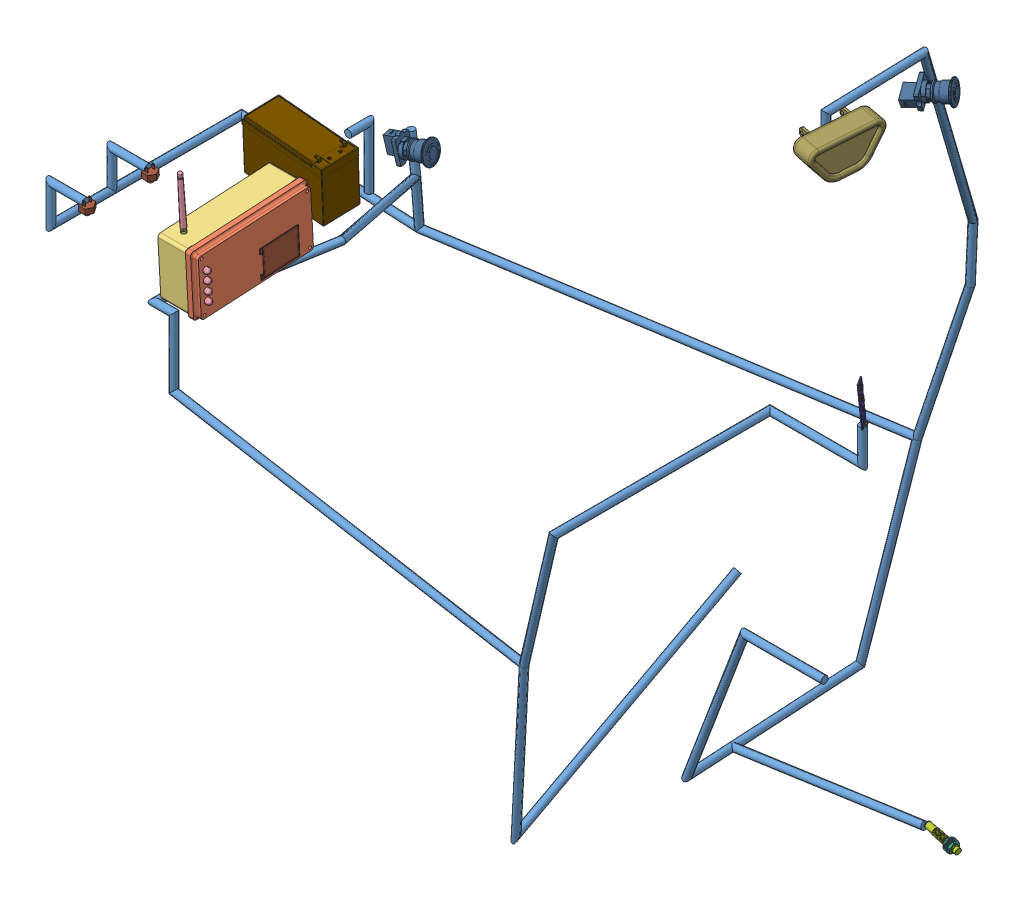
SolidWorks assembly Elétrica, configuration Valor predeterminado. Lengths in mm.
Overall size (1454.5 1161.28 753.93).
268 component instances, 110 part files, 2 mates.
Components (placement in the parent):
- Chicote elétrico-1: Chicote elétrico [Valor predeterminado<Como usinado>] at (-1115.3485 527.4134 1154.4841) size (1391.95 1161.28 753.93)
- Caixa_central-1: Caixa_central [Valor predeterminado] at (-1817.8838 498.4267 1275.2323) x (0 0.055168 -0.998477) z (1 0 0) size (209 203.94 79.26)
  - Caixa_frente-1: Caixa_frente [Valor predeterminado] at (-0.4442 -5.2196 199.5) size (209 109 19)
  - Caixa_traseira-1: Caixa_traseira [Valor predeterminado] at (-0.4442 -5.2196 199.5) size (204 104 52)
  - Placa_frontal_V1.0-1: Placa_frontal_V1.0 [Valor predeterminado] at (-98.9442 -54.7196 211.803) size (192 94 22.97)
    - Placa_frontal_V1.STEP-1: Placa_frontal_V1.STEP [Valor predeterminado] at origin size (192 94 22.97)
      - D1.STEP-1: D1.STEP [Valor predeterminado] at (11 74 0.803) x (-1 0 0) z (0 0 1) size (11 11 19.65)
        - Open CASCADE STEP translator 6.8 5.2.1.STEP-1: Open CASCADE STEP translator 6.8 5.2.1.STEP [Valor predeterminado] at origin size (11 11 19.65)
          - Body_1.STEP-1: Body_1.STEP [Valor predeterminado] at (1.25 0 -3.5) x (1 0 0) z (0 -1 0) size (11 19.65 11)
            - =_[0_1_1_3].STEP-1: =_[0_1_1_3].STEP [Valor predeterminado] at origin size (11 14 11)
            - =_[0_1_1_4].STEP-1: =_[0_1_1_4].STEP [Valor predeterminado] at origin size (0.5 5.65 0.5)
            - =_[0_1_1_5].STEP-1: =_[0_1_1_5].STEP [Valor predeterminado] at origin size (0.5 5.65 0.5)
            - =_[0_1_1_6].STEP-1: =_[0_1_1_6].STEP [Valor predeterminado] at origin size (0.6 0.65 0.5)
            - =_[0_1_1_7].STEP-1: =_[0_1_1_7].STEP [Valor predeterminado] at origin size (0.6 0.65 0.5)
      - D2.STEP-1: D2.STEP [Valor predeterminado] at (11 58 0.803) x (-1 0 0) z (0 0 1) size (11 11 19.65)
        - Open CASCADE STEP translator 6.8 5.3.1.STEP-1: Open CASCADE STEP translator 6.8 5.3.1.STEP [Valor predeterminado] at origin size (11 11 19.65)
          - Body_1.STEP-1: Body_1.STEP [Valor predeterminado] at (1.25 0 -3.5) x (1 0 0) z (0 -1 0) size (11 19.65 11)
            - =_[0_1_1_3].STEP-1: =_[0_1_1_3].STEP [Valor predeterminado] at origin size (11 14 11)
            - =_[0_1_1_4].STEP-1: =_[0_1_1_4].STEP [Valor predeterminado] at origin size (0.5 5.65 0.5)
            - =_[0_1_1_5].STEP-1: =_[0_1_1_5].STEP [Valor predeterminado] at origin size (0.5 5.65 0.5)
            - =_[0_1_1_6].STEP-1: =_[0_1_1_6].STEP [Valor predeterminado] at origin size (0.6 0.65 0.5)
            - =_[0_1_1_7].STEP-1: =_[0_1_1_7].STEP [Valor predeterminado] at origin size (0.6 0.65 0.5)
      - D3.STEP-1: D3.STEP [Valor predeterminado] at (11 41 0.803) x (-1 0 0) z (0 0 1) size (11 11 19.65)
        - Open CASCADE STEP translator 6.8 5.4.1.STEP-1: Open CASCADE STEP translator 6.8 5.4.1.STEP [Valor predeterminado] at origin size (11 11 19.65)
          - Body_1.STEP-1: Body_1.STEP [Valor predeterminado] at (1.25 0 -3.5) x (1 0 0) z (0 -1 0) size (11 19.65 11)
            - =_[0_1_1_3].STEP-1: =_[0_1_1_3].STEP [Valor predeterminado] at origin size (11 14 11)
            - =_[0_1_1_4].STEP-1: =_[0_1_1_4].STEP [Valor predeterminado] at origin size (0.5 5.65 0.5)
            - =_[0_1_1_5].STEP-1: =_[0_1_1_5].STEP [Valor predeterminado] at origin size (0.5 5.65 0.5)
            - =_[0_1_1_6].STEP-1: =_[0_1_1_6].STEP [Valor predeterminado] at origin size (0.6 0.65 0.5)
            - =_[0_1_1_7].STEP-1: =_[0_1_1_7].STEP [Valor predeterminado] at origin size (0.6 0.65 0.5)
      - D4.STEP-1: D4.STEP [Valor predeterminado] at (11 25 0.803) x (-1 0 0) z (0 0 1) size (11 11 19.65)
        - Open CASCADE STEP translator 6.8 5.5.1.STEP-1: Open CASCADE STEP translator 6.8 5.5.1.STEP [Valor predeterminado] at origin size (11 11 19.65)
          - Body_1.STEP-1: Body_1.STEP [Valor predeterminado] at (1.25 0 -3.5) x (1 0 0) z (0 -1 0) size (11 19.65 11)
            - =_[0_1_1_3].STEP-1: =_[0_1_1_3].STEP [Valor predeterminado] at origin size (11 14 11)
            - =_[0_1_1_4].STEP-1: =_[0_1_1_4].STEP [Valor predeterminado] at origin size (0.5 5.65 0.5)
            - =_[0_1_1_5].STEP-1: =_[0_1_1_5].STEP [Valor predeterminado] at origin size (0.5 5.65 0.5)
            - =_[0_1_1_6].STEP-1: =_[0_1_1_6].STEP [Valor predeterminado] at origin size (0.6 0.65 0.5)
            - =_[0_1_1_7].STEP-1: =_[0_1_1_7].STEP [Valor predeterminado] at origin size (0.6 0.65 0.5)
      - A1.STEP-1: A1.STEP [Valor predeterminado] at (96.2 24 0.803) size (85.9 50.19 11.99)
        - Open CASCADE STEP translator 6.8 5.6.1.STEP-1: Open CASCADE STEP translator 6.8 5.6.1.STEP [Valor predeterminado] at origin size (85.9 50.19 11.99)
          - Body_1-1.STEP-1: Body_1-1.STEP [Valor predeterminado] at (40.8 3.9 2.5) x (0 1 0) z (0 0 1) size (50.19 85.9 11.99)
            - 2.8in_TFT(Without_Glass)-_Tucked_Cable.STEP-1: 2.8in_TFT(Without_Glass)-_Tucked_Cable.STEP [Valor predeterminado] at (-0.0571 -2.2987 1.6256) x (-1 0 0) z (0 0 1) size (50.11 69.48 2.83)
              - SOLID.STEP-1: SOLID.STEP [Valor predeterminado] at origin size (0.29 0.77 0.02)
              - SOLID-0.STEP-1: SOLID-0.STEP [Valor predeterminado] at origin size (0.29 0.75 0.02)
              - SOLID-1.STEP-1: SOLID-1.STEP [Valor predeterminado] at origin size (50.11 69.48 2.72)
              - SOLID-2.STEP-1: SOLID-2.STEP [Valor predeterminado] at origin size (0.53 0.77 0.23)
            - 2.8_LCD_TFT_Module_-_Without_Glass.STEP-1: 2.8_LCD_TFT_Module_-_Without_Glass.STEP [Valor predeterminado] at origin size (50.14 85.9 10.67)
            - 5035000993.STEP-1: 5035000993.STEP [Valor predeterminado] at (3.5564 -3.3047 -2.85) x (0 1 0) z (0 0 -1) size (28.6 21.52 2.95)
            - 0603_Resistor.STEP-1: 0603_Resistor.STEP [Valor predeterminado] at (-2.2311 -3.165 0.0025) x (-1 0 0) z (0 0 -1) size (1.6 0.85 0.56)
            - 0603_Capacitor.STEP-1: 0603_Capacitor.STEP [Valor predeterminado] at (-14.5217 25.6289 0.0025) x (1 0 0) z (0 0 -1) size (1.6 0.84 0.84)
            - 0603_Capacitor.STEP-2: 0603_Capacitor.STEP [Valor predeterminado] at (-2.484 19.738 0.0025) x (-1 0 0) z (0 0 -1) size (1.6 0.84 0.84)
            - 0603_Resistor.STEP-2: 0603_Resistor.STEP [Valor predeterminado] at (-3.8795 -4.7617 0.0025) x (1 0 0) z (0 0 -1) size (1.6 0.85 0.56)
            - 0603_Resistor.STEP-3: 0603_Resistor.STEP [Valor predeterminado] at (-2.3355 -0.9936 0.0025) x (-1 0 0) z (0 0 -1) size (1.6 0.85 0.56)
            - 0603_Resistor.STEP-4: 0603_Resistor.STEP [Valor predeterminado] at (-12.9341 26.6747 0.0025) x (-1 0 0) z (0 0 -1) size (1.6 0.85 0.56)
            - 0603_Resistor.STEP-5: 0603_Resistor.STEP [Valor predeterminado] at (4.5338 19.5922 0.0025) x (-1 0 0) z (0 0 -1) size (1.6 0.85 0.56)
            - 0603_Resistor.STEP-6: 0603_Resistor.STEP [Valor predeterminado] at (4.3803 26.5372 0.0025) x (-1 0 0) z (0 0 -1) size (1.6 0.85 0.56)
            - SOT23-3.STEP-1: SOT23-3.STEP [Valor predeterminado] at (3.6167 23.9432 0.105) x (0.003406 0.999994 0) z (0 0 -1) size (2.87 3.01 1.21)
            - SOT23-3.STEP-2: SOT23-3.STEP [Valor predeterminado] at (-3.3735 23.944 0.105) x (0.999985 -0.005499 0) z (0 0 -1) size (2.87 3.01 1.21)
      - DISPLAY.STEP-1: DISPLAY.STEP [Valor predeterminado] at (41 45 -0.803) x (0 -1 0) z (0 0 -1) size (22.17 5.84 10.21)
        - Open CASCADE STEP translator 6.8 5.7.1.STEP-1: Open CASCADE STEP translator 6.8 5.7.1.STEP [Valor predeterminado] at origin size (22.17 5.84 10.21)
          - Body_1-3.STEP-1: Body_1-3.STEP [Valor predeterminado] at (8.8 0 0) size (22.17 5.84 10.21)
      - LEDS.STEP-1: LEDS.STEP [Valor predeterminado] at (41 61 -0.803) x (0 -1 0) z (0 0 -1) size (12.17 5.84 10.21)
        - Open CASCADE STEP translator 6.8 5.8.1.STEP-1: Open CASCADE STEP translator 6.8 5.8.1.STEP [Valor predeterminado] at origin size (12.17 5.84 10.21)
          - Body_1-4.STEP-1: Body_1-4.STEP [Valor predeterminado] at (3.8 0 0) size (12.17 5.84 10.21)
      - R1.STEP-1: R1.STEP [Valor predeterminado] at (32 58 0.803) x (-1 0 0) z (0 0 1) size (10.82 1.37 5.33)
        - Open CASCADE STEP translator 6.8 5.9.1.STEP-1: Open CASCADE STEP translator 6.8 5.9.1.STEP [Valor predeterminado] at origin size (10.82 1.37 5.33)
          - Body_1-5.STEP-1: Body_1-5.STEP [Valor predeterminado] at origin size (5.08 1.37 1.37)
          - Pin_1.STEP-1: Pin_1.STEP [Valor predeterminado] at origin size (3.2 0.66 4.98)
          - Pin_2.STEP-1: Pin_2.STEP [Valor predeterminado] at (20.32 0 0) x (-1 0 0) z (0 0 1) size (3.2 0.66 4.98)
      - R2.STEP-1: R2.STEP [Valor predeterminado] at (32 52 0.803) x (-1 0 0) z (0 0 1) size (10.82 1.37 5.33)
        - Open CASCADE STEP translator 6.8 5.9.1.STEP-1: Open CASCADE STEP translator 6.8 5.9.1.STEP [Valor predeterminado] at origin size (10.82 1.37 5.33)
          - Body_1-5.STEP-1: Body_1-5.STEP [Valor predeterminado] at origin size (5.08 1.37 1.37)
          - Pin_1.STEP-1: Pin_1.STEP [Valor predeterminado] at origin size (3.2 0.66 4.98)
          - Pin_2.STEP-1: Pin_2.STEP [Valor predeterminado] at (20.32 0 0) x (-1 0 0) z (0 0 1) size (3.2 0.66 4.98)
      - R3.STEP-1: R3.STEP [Valor predeterminado] at (32 46 0.803) x (-1 0 0) z (0 0 1) size (10.82 1.37 5.33)
        - Open CASCADE STEP translator 6.8 5.9.1.STEP-1: Open CASCADE STEP translator 6.8 5.9.1.STEP [Valor predeterminado] at origin size (10.82 1.37 5.33)
          - Body_1-5.STEP-1: Body_1-5.STEP [Valor predeterminado] at origin size (5.08 1.37 1.37)
          - Pin_1.STEP-1: Pin_1.STEP [Valor predeterminado] at origin size (3.2 0.66 4.98)
          - Pin_2.STEP-1: Pin_2.STEP [Valor predeterminado] at (20.32 0 0) x (-1 0 0) z (0 0 1) size (3.2 0.66 4.98)
      - R4.STEP-1: R4.STEP [Valor predeterminado] at (32 39 0.803) x (-1 0 0) z (0 0 1) size (10.82 1.37 5.33)
        - Open CASCADE STEP translator 6.8 5.9.1.STEP-1: Open CASCADE STEP translator 6.8 5.9.1.STEP [Valor predeterminado] at origin size (10.82 1.37 5.33)
          - Body_1-5.STEP-1: Body_1-5.STEP [Valor predeterminado] at origin size (5.08 1.37 1.37)
          - Pin_1.STEP-1: Pin_1.STEP [Valor predeterminado] at origin size (3.2 0.66 4.98)
          - Pin_2.STEP-1: Pin_2.STEP [Valor predeterminado] at (20.32 0 0) x (-1 0 0) z (0 0 1) size (3.2 0.66 4.98)
      - A2.STEP-1: A2.STEP [Valor predeterminado] at (156.8 24.1 -0.803) x (-1 0 0) z (0 0 -1) size (85.9 50.19 11.99)
        - Open CASCADE STEP translator 6.8 5.13.1.STEP-1: Open CASCADE STEP translator 6.8 5.13.1.STEP [Valor predeterminado] at origin size (85.9 50.19 11.99)
          - Body_1-1.STEP-1: Body_1-1.STEP [Valor predeterminado] at (40.8 3.9 2.5) x (0 1 0) z (0 0 1) size (50.19 85.9 11.99)
            - 2.8in_TFT(Without_Glass)-_Tucked_Cable.STEP-1: 2.8in_TFT(Without_Glass)-_Tucked_Cable.STEP [Valor predeterminado] at (-0.0571 -2.2987 1.6256) x (-1 0 0) z (0 0 1) size (50.11 69.48 2.83)
              - SOLID.STEP-1: SOLID.STEP [Valor predeterminado] at origin size (0.29 0.77 0.02)
              - SOLID-0.STEP-1: SOLID-0.STEP [Valor predeterminado] at origin size (0.29 0.75 0.02)
              - SOLID-1.STEP-1: SOLID-1.STEP [Valor predeterminado] at origin size (50.11 69.48 2.72)
              - SOLID-2.STEP-1: SOLID-2.STEP [Valor predeterminado] at origin size (0.53 0.77 0.23)
            - 2.8_LCD_TFT_Module_-_Without_Glass.STEP-1: 2.8_LCD_TFT_Module_-_Without_Glass.STEP [Valor predeterminado] at origin size (50.14 85.9 10.67)
            - 5035000993.STEP-1: 5035000993.STEP [Valor predeterminado] at (3.5564 -3.3047 -2.85) x (0 1 0) z (0 0 -1) size (28.6 21.52 2.95)
            - 0603_Resistor.STEP-1: 0603_Resistor.STEP [Valor predeterminado] at (-2.2311 -3.165 0.0025) x (-1 0 0) z (0 0 -1) size (1.6 0.85 0.56)
            - 0603_Capacitor.STEP-1: 0603_Capacitor.STEP [Valor predeterminado] at (-14.5217 25.6289 0.0025) x (1 0 0) z (0 0 -1) size (1.6 0.84 0.84)
            - 0603_Capacitor.STEP-2: 0603_Capacitor.STEP [Valor predeterminado] at (-2.484 19.738 0.0025) x (-1 0 0) z (0 0 -1) size (1.6 0.84 0.84)
            - 0603_Resistor.STEP-2: 0603_Resistor.STEP [Valor predeterminado] at (-3.8795 -4.7617 0.0025) x (1 0 0) z (0 0 -1) size (1.6 0.85 0.56)
            - 0603_Resistor.STEP-3: 0603_Resistor.STEP [Valor predeterminado] at (-2.3355 -0.9936 0.0025) x (-1 0 0) z (0 0 -1) size (1.6 0.85 0.56)
            - 0603_Resistor.STEP-4: 0603_Resistor.STEP [Valor predeterminado] at (-12.9341 26.6747 0.0025) x (-1 0 0) z (0 0 -1) size (1.6 0.85 0.56)
            - 0603_Resistor.STEP-5: 0603_Resistor.STEP [Valor predeterminado] at (4.5338 19.5922 0.0025) x (-1 0 0) z (0 0 -1) size (1.6 0.85 0.56)
            - 0603_Resistor.STEP-6: 0603_Resistor.STEP [Valor predeterminado] at (4.3803 26.5372 0.0025) x (-1 0 0) z (0 0 -1) size (1.6 0.85 0.56)
            - SOT23-3.STEP-1: SOT23-3.STEP [Valor predeterminado] at (3.6167 23.9432 0.105) x (0.003406 0.999994 0) z (0 0 -1) size (2.87 3.01 1.21)
            - SOT23-3.STEP-2: SOT23-3.STEP [Valor predeterminado] at (-3.3735 23.944 0.105) x (0.999985 -0.005499 0) z (0 0 -1) size (2.87 3.01 1.21)
      - Layer_1.STEP-1: Layer_1.STEP [Valor predeterminado] at origin size (192 94 1.61)
  - Placa_central_V2.0-1: Placa_central_V2.0 [Valor predeterminado] at (-39 -51.2196 160.303) size (78.1 88 28.62)
    - Projeto_V2(2)^Placa_central_V2.0-1: Projeto_V2(2)^Placa_central_V2.0 [Valor predeterminado] at origin size (78.1 88 28.62) (virtual)
      - U1^Projeto_V2(2)_Placa_central_V2.0-1: U1^Projeto_V2(2)_Placa_central_V2.0 [Valor predeterminado] at (28.5 68.42 0.803) size (23 57.8 17) (virtual)
        - Open CASCADE STEP translator 6.8 1.2.1^U1_Projeto_V2(2)_Placa_central_V2.0-1: Open CASCADE STEP translator 6.8 1.2.1^U1_Projeto_V2(2)_Placa_central_V2.0 [Valor predeterminado] at origin size (23 57.8 17) (virtual)
          - Body_1^Open CASCADE STEP translator 6.8 1.2.1_U1_Projeto_V2(2)_Placa_central_V2.0-1: Body_1^Open CASCADE STEP translator 6.8 1.2.1_U1_Projeto_V2(2)_Placa_central_V2.0 [Valor predeterminado] at (8 -27.5 5) x (-1 0 0) z (0 0 1) size (23 57.8 17) (virtual)
      - SENSORES^Projeto_V2(2)_Placa_central_V2.0-1: SENSORES^Projeto_V2(2)_Placa_central_V2.0 [Valor predeterminado] at (68.97 22.65 0.803) x (0 -1 0) z (0 0 1) size (17.17 5.84 10.21) (virtual)
        - Open CASCADE STEP translator 6.8 1.3.1^SENSORES_Projeto_V2(2)_Placa_central_V2.0-1: Open CASCADE STEP translator 6.8 1.3.1^SENSORES_Projeto_V2(2)_Placa_central_V2.0 [Valor predeterminado] at origin size (17.17 5.84 10.21) (virtual)
          - Body_1-0^Open CASCADE STEP translator 6.8 1.3.1_SENSORES_Projeto_V2(2)_Placa_central_V2.0-1: Body_1-0^Open CASCADE STEP translator 6.8 1.3.1_SENSORES_Projeto_V2(2)_Placa_central_V2.0 [Valor predeterminado] at (6.3 0 0) size (17.17 5.84 10.21) (virtual)
      - DISPLAY^Projeto_V2(2)_Placa_central_V2.0-1: DISPLAY^Projeto_V2(2)_Placa_central_V2.0 [Valor predeterminado] at (8.05 52.39 0.803) x (0 1 0) z (0 0 1) size (22.17 5.84 10.21) (virtual)
        - Open CASCADE STEP translator 6.8 1.4.1^DISPLAY_Projeto_V2(2)_Placa_central_V2.0-1: Open CASCADE STEP translator 6.8 1.4.1^DISPLAY_Projeto_V2(2)_Placa_central_V2.0 [Valor predeterminado] at origin size (22.17 5.84 10.21) (virtual)
          - Body_1-1^Open CASCADE STEP translator 6.8 1.4.1_DISPLAY_Projeto_V2(2)_Placa_central_V2.0-1: Body_1-1^Open CASCADE STEP translator 6.8 1.4.1_DISPLAY_Projeto_V2(2)_Placa_central_V2.0 [Valor predeterminado] at (9 0 0) size (22.17 5.84 10.21) (virtual)
      - EXTRA_1^Projeto_V2(2)_Placa_central_V2.0-1: EXTRA_1^Projeto_V2(2)_Placa_central_V2.0 [Valor predeterminado] at (69.08 71.14 0.803) x (0 -1 0) z (0 0 1) size (22.17 5.84 10.21) (virtual)
        - Open CASCADE STEP translator 6.8 1.5.1^EXTRA_1_Projeto_V2(2)_Placa_central_V2.0-1: Open CASCADE STEP translator 6.8 1.5.1^EXTRA_1_Projeto_V2(2)_Placa_central_V2.0 [Valor predeterminado] at origin size (22.17 5.84 10.21) (virtual)
          - Body_1-1^Open CASCADE STEP translator 6.8 1.5.1_EXTRA_1_Projeto_V2(2)_Placa_central_V2.0-1: Body_1-1^Open CASCADE STEP translator 6.8 1.5.1_EXTRA_1_Projeto_V2(2)_Placa_central_V2.0 [Valor predeterminado] at (9 0 0) size (22.17 5.84 10.21) (virtual)
      - EXTRA_2^Projeto_V2(2)_Placa_central_V2.0-1: EXTRA_2^Projeto_V2(2)_Placa_central_V2.0 [Valor predeterminado] at (68.98 46.93 0.803) x (0 -1 0) z (0 0 1) size (22.17 5.84 10.21) (virtual)
        - Open CASCADE STEP translator 6.8 1.6.1^EXTRA_2_Projeto_V2(2)_Placa_central_V2.0-1: Open CASCADE STEP translator 6.8 1.6.1^EXTRA_2_Projeto_V2(2)_Placa_central_V2.0 [Valor predeterminado] at origin size (22.17 5.84 10.21) (virtual)
          - Body_1-1^Open CASCADE STEP translator 6.8 1.6.1_EXTRA_2_Projeto_V2(2)_Placa_central_V2.0-1: Body_1-1^Open CASCADE STEP translator 6.8 1.6.1_EXTRA_2_Projeto_V2(2)_Placa_central_V2.0 [Valor predeterminado] at (9 0 0) size (22.17 5.84 10.21) (virtual)
      - MPU^Projeto_V2(2)_Placa_central_V2.0-1: MPU^Projeto_V2(2)_Placa_central_V2.0 [Valor predeterminado] at (57.58 6.7 0.803) x (-1 0 0) z (0 0 1) size (12.17 5.84 10.21) (virtual)
        - Open CASCADE STEP translator 6.8 1.7.1^MPU_Projeto_V2(2)_Placa_central_V2.0-1: Open CASCADE STEP translator 6.8 1.7.1^MPU_Projeto_V2(2)_Placa_central_V2.0 [Valor predeterminado] at origin size (12.17 5.84 10.21) (virtual)
          - Body_1-2^Open CASCADE STEP translator 6.8 1.7.1_MPU_Projeto_V2(2)_Placa_central_V2.0-1: Body_1-2^Open CASCADE STEP translator 6.8 1.7.1_MPU_Projeto_V2(2)_Placa_central_V2.0 [Valor predeterminado] at (3.8 0 0) size (12.17 5.84 10.21) (virtual)
      - RADIO^Projeto_V2(2)_Placa_central_V2.0-1: RADIO^Projeto_V2(2)_Placa_central_V2.0 [Valor predeterminado] at (8.06 29.74 0.803) x (0 1 0) z (0 0 1) size (19.67 5.84 10.21) (virtual)
        - Open CASCADE STEP translator 6.8 1.8.1^RADIO_Projeto_V2(2)_Placa_central_V2.0-1: Open CASCADE STEP translator 6.8 1.8.1^RADIO_Projeto_V2(2)_Placa_central_V2.0 [Valor predeterminado] at origin size (19.67 5.84 10.21) (virtual)
          - Body_1-3^Open CASCADE STEP translator 6.8 1.8.1_RADIO_Projeto_V2(2)_Placa_central_V2.0-1: Body_1-3^Open CASCADE STEP translator 6.8 1.8.1_RADIO_Projeto_V2(2)_Placa_central_V2.0 [Valor predeterminado] at (7.5 0 0) size (19.67 5.84 10.21) (virtual)
      - GRAVADOR^Projeto_V2(2)_Placa_central_V2.0-1: GRAVADOR^Projeto_V2(2)_Placa_central_V2.0 [Valor predeterminado] at (29.79 6.81 0.803) x (-1 0 0) z (0 0 1) size (17.17 5.84 10.21) (virtual)
        - Open CASCADE STEP translator 6.8 1.9.1^GRAVADOR_Projeto_V2(2)_Placa_central_V2.0-1: Open CASCADE STEP translator 6.8 1.9.1^GRAVADOR_Projeto_V2(2)_Placa_central_V2.0 [Valor predeterminado] at origin size (17.17 5.84 10.21) (virtual)
          - Body_1-0^Open CASCADE STEP translator 6.8 1.9.1_GRAVADOR_Projeto_V2(2)_Placa_central_V2.0-1: Body_1-0^Open CASCADE STEP translator 6.8 1.9.1_GRAVADOR_Projeto_V2(2)_Placa_central_V2.0 [Valor predeterminado] at (6.3 0 0) size (17.17 5.84 10.21) (virtual)
      - GRAVACAO^Projeto_V2(2)_Placa_central_V2.0-1: GRAVACAO^Projeto_V2(2)_Placa_central_V2.0 [Valor predeterminado] at (37.91 8.34 0.803) size (5.08 2.54 11.54) (virtual)
        - Open CASCADE STEP translator 6.8 1.10.1^GRAVACAO_Projeto_V2(2)_Placa_central_V2.0-1: Open CASCADE STEP translator 6.8 1.10.1^GRAVACAO_Projeto_V2(2)_Placa_central_V2.0 [Valor predeterminado] at origin size (5.08 2.54 11.54) (virtual)
          - Body_1-4^Open CASCADE STEP translator 6.8 1.10.1_GRAVACAO_Projeto_V2(2)_Placa_central_V2.0-1: Body_1-4^Open CASCADE STEP translator 6.8 1.10.1_GRAVACAO_Projeto_V2(2)_Placa_central_V2.0 [Valor predeterminado] at (2.5 0 0) x (1 0 0) z (0 -1 0) size (5.08 11.54 2.54) (virtual)
            - =_[0_1_1_3]^Body_1-4_Open CASCADE STEP translator 6.8 1.10.1_GRAVACAO_Projeto_V2(2)_Placa_central_V2.0-1: =_[0_1_1_3]^Body_1-4_Open CASCADE STEP translator 6.8 1.10.1_GRAVACAO_Projeto_V2(2)_Placa_central_V2.0 [Valor predeterminado] at origin size (0.64 3.3 0.64) (virtual)
            - =_[0_1_1_4]^Body_1-4_Open CASCADE STEP translator 6.8 1.10.1_GRAVACAO_Projeto_V2(2)_Placa_central_V2.0-1: =_[0_1_1_4]^Body_1-4_Open CASCADE STEP translator 6.8 1.10.1_GRAVACAO_Projeto_V2(2)_Placa_central_V2.0 [Valor predeterminado] at origin size (0.64 6 0.64) (virtual)
            - =_[0_1_1_5]^Body_1-4_Open CASCADE STEP translator 6.8 1.10.1_GRAVACAO_Projeto_V2(2)_Placa_central_V2.0-1: =_[0_1_1_5]^Body_1-4_Open CASCADE STEP translator 6.8 1.10.1_GRAVACAO_Projeto_V2(2)_Placa_central_V2.0 [Valor predeterminado] at origin size (2.54 2.54 2.54) (virtual)
            - =_[0_1_1_6]^Body_1-4_Open CASCADE STEP translator 6.8 1.10.1_GRAVACAO_Projeto_V2(2)_Placa_central_V2.0-1: =_[0_1_1_6]^Body_1-4_Open CASCADE STEP translator 6.8 1.10.1_GRAVACAO_Projeto_V2(2)_Placa_central_V2.0 [Valor predeterminado] at origin size (2.54 2.54 2.54) (virtual)
            - =_[0_1_1_7]^Body_1-4_Open CASCADE STEP translator 6.8 1.10.1_GRAVACAO_Projeto_V2(2)_Placa_central_V2.0-1: =_[0_1_1_7]^Body_1-4_Open CASCADE STEP translator 6.8 1.10.1_GRAVACAO_Projeto_V2(2)_Placa_central_V2.0 [Valor predeterminado] at origin size (0.64 3.3 0.64) (virtual)
            - =_[0_1_1_8]^Body_1-4_Open CASCADE STEP translator 6.8 1.10.1_GRAVACAO_Projeto_V2(2)_Placa_central_V2.0-1: =_[0_1_1_8]^Body_1-4_Open CASCADE STEP translator 6.8 1.10.1_GRAVACAO_Projeto_V2(2)_Placa_central_V2.0 [Valor predeterminado] at origin size (0.64 6 0.64) (virtual)
      - BATERIA_12V^Projeto_V2(2)_Placa_central_V2.0-1: BATERIA_12V^Projeto_V2(2)_Placa_central_V2.0 [Valor predeterminado] at (10.06 80.63 0.803) size (7.17 5.84 10.21) (virtual)
        - Open CASCADE STEP translator 6.8 1.11.1^BATERIA_12V_Projeto_V2(2)_Placa_central_V2.0-1: Open CASCADE STEP translator 6.8 1.11.1^BATERIA_12V_Projeto_V2(2)_Placa_central_V2.0 [Valor predeterminado] at origin size (7.17 5.84 10.21) (virtual)
          - Body_1-5^Open CASCADE STEP translator 6.8 1.11.1_BATERIA_12V_Projeto_V2(2)_Placa_central_V2.0-1: Body_1-5^Open CASCADE STEP translator 6.8 1.11.1_BATERIA_12V_Projeto_V2(2)_Placa_central_V2.0 [Valor predeterminado] at (1.2 0 0) size (7.17 5.84 10.21) (virtual)
      - D1^Projeto_V2(2)_Placa_central_V2.0-1: D1^Projeto_V2(2)_Placa_central_V2.0 [Valor predeterminado] at (28.89 76.68 0.803) x (-1 0 0) z (0 0 1) size (11.02 2.72 5.32) (virtual)
        - Open CASCADE STEP translator 6.8 1.12.1^D1_Projeto_V2(2)_Placa_central_V2.0-1: Open CASCADE STEP translator 6.8 1.12.1^D1_Projeto_V2(2)_Placa_central_V2.0 [Valor predeterminado] at origin size (11.02 2.72 5.32) (virtual)
          - Body_1-6^Open CASCADE STEP translator 6.8 1.12.1_D1_Projeto_V2(2)_Placa_central_V2.0-1: Body_1-6^Open CASCADE STEP translator 6.8 1.12.1_D1_Projeto_V2(2)_Placa_central_V2.0 [Valor predeterminado] at (10.1 0 0) size (11.02 2.72 5.32) (virtual)
      - C4^Projeto_V2(2)_Placa_central_V2.0-1: C4^Projeto_V2(2)_Placa_central_V2.0 [Valor predeterminado] at (24.23 81.25 0.803) x (0 1 0) z (0 0 1) size (5.84 5.84 8.33) (virtual)
        - Open CASCADE STEP translator 6.8 1.13.1^C4_Projeto_V2(2)_Placa_central_V2.0-1: Open CASCADE STEP translator 6.8 1.13.1^C4_Projeto_V2(2)_Placa_central_V2.0 [Valor predeterminado] at origin size (5.84 5.84 8.33) (virtual)
          - Body_1-7^Open CASCADE STEP translator 6.8 1.13.1_C4_Projeto_V2(2)_Placa_central_V2.0-1: Body_1-7^Open CASCADE STEP translator 6.8 1.13.1_C4_Projeto_V2(2)_Placa_central_V2.0 [Valor predeterminado] at origin size (5.84 5.84 3) (virtual)
          - Pin_1^Open CASCADE STEP translator 6.8 1.13.1_C4_Projeto_V2(2)_Placa_central_V2.0-1: Pin_1^Open CASCADE STEP translator 6.8 1.13.1_C4_Projeto_V2(2)_Placa_central_V2.0 [Valor predeterminado] x (0 -1 0) z (0 0 1) size (0.66 0.66 7.16) (virtual)
          - Pin_2^Open CASCADE STEP translator 6.8 1.13.1_C4_Projeto_V2(2)_Placa_central_V2.0-1: Pin_2^Open CASCADE STEP translator 6.8 1.13.1_C4_Projeto_V2(2)_Placa_central_V2.0 [Valor predeterminado] at (3.175 3.175 0) x (0 -1 0) z (0 0 1) size (0.66 0.66 7.16) (virtual)
      - U2^Projeto_V2(2)_Placa_central_V2.0-1: U2^Projeto_V2(2)_Placa_central_V2.0 [Valor predeterminado] at (68.11 83 0.803) size (9.97 4.45 28.62) (virtual)
        - Open CASCADE STEP translator 6.8 1.14.1^U2_Projeto_V2(2)_Placa_central_V2.0-1: Open CASCADE STEP translator 6.8 1.14.1^U2_Projeto_V2(2)_Placa_central_V2.0 [Valor predeterminado] at origin size (9.97 4.45 28.62) (virtual)
          - Body_1-8^Open CASCADE STEP translator 6.8 1.14.1_U2_Projeto_V2(2)_Placa_central_V2.0-1: Body_1-8^Open CASCADE STEP translator 6.8 1.14.1_U2_Projeto_V2(2)_Placa_central_V2.0 [Valor predeterminado] at (0 3 3.5) x (1 0 0) z (0 -1 0) size (9.97 28.62 4.45) (virtual)
      - U3^Projeto_V2(2)_Placa_central_V2.0-1: U3^Projeto_V2(2)_Placa_central_V2.0 [Valor predeterminado] at (55.88 83 0.803) size (9.97 4.45 28.62) (virtual)
        - Open CASCADE STEP translator 6.8 1.15.1^U3_Projeto_V2(2)_Placa_central_V2.0-1: Open CASCADE STEP translator 6.8 1.15.1^U3_Projeto_V2(2)_Placa_central_V2.0 [Valor predeterminado] at origin size (9.97 4.45 28.62) (virtual)
          - Body_1-8^Open CASCADE STEP translator 6.8 1.15.1_U3_Projeto_V2(2)_Placa_central_V2.0-1: Body_1-8^Open CASCADE STEP translator 6.8 1.15.1_U3_Projeto_V2(2)_Placa_central_V2.0 [Valor predeterminado] at (0 3 3.5) x (1 0 0) z (0 -1 0) size (9.97 28.62 4.45) (virtual)
      - BATERIA^Projeto_V2(2)_Placa_central_V2.0-1: BATERIA^Projeto_V2(2)_Placa_central_V2.0 [Valor predeterminado] at (37.95 5.08 0.803) size (5.08 2.54 11.54) (virtual)
        - Open CASCADE STEP translator 6.8 1.16.1^BATERIA_Projeto_V2(2)_Placa_central_V2.0-1: Open CASCADE STEP translator 6.8 1.16.1^BATERIA_Projeto_V2(2)_Placa_central_V2.0 [Valor predeterminado] at origin size (5.08 2.54 11.54) (virtual)
          - Body_1-4^Open CASCADE STEP translator 6.8 1.16.1_BATERIA_Projeto_V2(2)_Placa_central_V2.0-1: Body_1-4^Open CASCADE STEP translator 6.8 1.16.1_BATERIA_Projeto_V2(2)_Placa_central_V2.0 [Valor predeterminado] at (2.5 0 0) x (1 0 0) z (0 -1 0) size (5.08 11.54 2.54) (virtual)
            - =_[0_1_1_3]^Body_1-4_Open CASCADE STEP translator 6.8 1.16.1_BATERIA_Projeto_V2(2)_Placa_central_V2.0-1: =_[0_1_1_3]^Body_1-4_Open CASCADE STEP translator 6.8 1.16.1_BATERIA_Projeto_V2(2)_Placa_central_V2.0 [Valor predeterminado] at origin size (0.64 3.3 0.64) (virtual)
            - =_[0_1_1_4]^Body_1-4_Open CASCADE STEP translator 6.8 1.16.1_BATERIA_Projeto_V2(2)_Placa_central_V2.0-1: =_[0_1_1_4]^Body_1-4_Open CASCADE STEP translator 6.8 1.16.1_BATERIA_Projeto_V2(2)_Placa_central_V2.0 [Valor predeterminado] at origin size (0.64 6 0.64) (virtual)
            - =_[0_1_1_5]^Body_1-4_Open CASCADE STEP translator 6.8 1.16.1_BATERIA_Projeto_V2(2)_Placa_central_V2.0-1: =_[0_1_1_5]^Body_1-4_Open CASCADE STEP translator 6.8 1.16.1_BATERIA_Projeto_V2(2)_Placa_central_V2.0 [Valor predeterminado] at origin size (2.54 2.54 2.54) (virtual)
            - =_[0_1_1_6]^Body_1-4_Open CASCADE STEP translator 6.8 1.16.1_BATERIA_Projeto_V2(2)_Placa_central_V2.0-1: =_[0_1_1_6]^Body_1-4_Open CASCADE STEP translator 6.8 1.16.1_BATERIA_Projeto_V2(2)_Placa_central_V2.0 [Valor predeterminado] at origin size (2.54 2.54 2.54) (virtual)
            - =_[0_1_1_7]^Body_1-4_Open CASCADE STEP translator 6.8 1.16.1_BATERIA_Projeto_V2(2)_Placa_central_V2.0-1: =_[0_1_1_7]^Body_1-4_Open CASCADE STEP translator 6.8 1.16.1_BATERIA_Projeto_V2(2)_Placa_central_V2.0 [Valor predeterminado] at origin size (0.64 3.3 0.64) (virtual)
            - =_[0_1_1_8]^Body_1-4_Open CASCADE STEP translator 6.8 1.16.1_BATERIA_Projeto_V2(2)_Placa_central_V2.0-1: =_[0_1_1_8]^Body_1-4_Open CASCADE STEP translator 6.8 1.16.1_BATERIA_Projeto_V2(2)_Placa_central_V2.0 [Valor predeterminado] at origin size (0.64 6 0.64) (virtual)
      - C6^Projeto_V2(2)_Placa_central_V2.0-1: C6^Projeto_V2(2)_Placa_central_V2.0 [Valor predeterminado] at (36.29 81.25 0.803) x (0 1 0) z (0 0 1) size (5.84 5.84 8.33) (virtual)
        - Open CASCADE STEP translator 6.8 1.13.1^C6_Projeto_V2(2)_Placa_central_V2.0-1: Open CASCADE STEP translator 6.8 1.13.1^C6_Projeto_V2(2)_Placa_central_V2.0 [Valor predeterminado] at origin size (5.84 5.84 8.33) (virtual)
          - Body_1-7^Open CASCADE STEP translator 6.8 1.13.1_C6_Projeto_V2(2)_Placa_central_V2.0-1: Body_1-7^Open CASCADE STEP translator 6.8 1.13.1_C6_Projeto_V2(2)_Placa_central_V2.0 [Valor predeterminado] at origin size (5.84 5.84 3) (virtual)
          - Pin_1^Open CASCADE STEP translator 6.8 1.13.1_C6_Projeto_V2(2)_Placa_central_V2.0-1: Pin_1^Open CASCADE STEP translator 6.8 1.13.1_C6_Projeto_V2(2)_Placa_central_V2.0 [Valor predeterminado] x (0 -1 0) z (0 0 1) size (0.66 0.66 7.16) (virtual)
          - Pin_2^Open CASCADE STEP translator 6.8 1.13.1_C6_Projeto_V2(2)_Placa_central_V2.0-1: Pin_2^Open CASCADE STEP translator 6.8 1.13.1_C6_Projeto_V2(2)_Placa_central_V2.0 [Valor predeterminado] at (3.175 3.175 0) x (0 -1 0) z (0 0 1) size (0.66 0.66 7.16) (virtual)
      - C1^Projeto_V2(2)_Placa_central_V2.0-1: C1^Projeto_V2(2)_Placa_central_V2.0 [Valor predeterminado] at (51.16 75.55 0.803) size (5 2 7.75) (virtual)
        - Open CASCADE STEP translator 6.8 1.18.1^C1_Projeto_V2(2)_Placa_central_V2.0-1: Open CASCADE STEP translator 6.8 1.18.1^C1_Projeto_V2(2)_Placa_central_V2.0 [Valor predeterminado] at origin size (5 2 7.75) (virtual)
          - Body_1-9^Open CASCADE STEP translator 6.8 1.18.1_C1_Projeto_V2(2)_Placa_central_V2.0-1: Body_1-9^Open CASCADE STEP translator 6.8 1.18.1_C1_Projeto_V2(2)_Placa_central_V2.0 [Valor predeterminado] at (1.905 -1.905 0) x (0 1 0) z (0 0 1) size (2 5 5) (virtual)
          - Pin_1-10^Open CASCADE STEP translator 6.8 1.18.1_C1_Projeto_V2(2)_Placa_central_V2.0-1: Pin_1-10^Open CASCADE STEP translator 6.8 1.18.1_C1_Projeto_V2(2)_Placa_central_V2.0 [Valor predeterminado] x (0 -1 0) z (0 0 1) size (0.5 0.5 5.5) (virtual)
          - Pin_2-11^Open CASCADE STEP translator 6.8 1.18.1_C1_Projeto_V2(2)_Placa_central_V2.0-1: Pin_2-11^Open CASCADE STEP translator 6.8 1.18.1_C1_Projeto_V2(2)_Placa_central_V2.0 [Valor predeterminado] at (3.81 3.81 0) x (0 -1 0) z (0 0 1) size (0.5 0.5 5.5) (virtual)
      - C2^Projeto_V2(2)_Placa_central_V2.0-1: C2^Projeto_V2(2)_Placa_central_V2.0 [Valor predeterminado] at (42.39 75.54 0.803) size (5 2 7.75) (virtual)
        - Open CASCADE STEP translator 6.8 1.18.1^C2_Projeto_V2(2)_Placa_central_V2.0-1: Open CASCADE STEP translator 6.8 1.18.1^C2_Projeto_V2(2)_Placa_central_V2.0 [Valor predeterminado] at origin size (5 2 7.75) (virtual)
          - Body_1-9^Open CASCADE STEP translator 6.8 1.18.1_C2_Projeto_V2(2)_Placa_central_V2.0-1: Body_1-9^Open CASCADE STEP translator 6.8 1.18.1_C2_Projeto_V2(2)_Placa_central_V2.0 [Valor predeterminado] at (1.905 -1.905 0) x (0 1 0) z (0 0 1) size (2 5 5) (virtual)
          - Pin_1-10^Open CASCADE STEP translator 6.8 1.18.1_C2_Projeto_V2(2)_Placa_central_V2.0-1: Pin_1-10^Open CASCADE STEP translator 6.8 1.18.1_C2_Projeto_V2(2)_Placa_central_V2.0 [Valor predeterminado] x (0 -1 0) z (0 0 1) size (0.5 0.5 5.5) (virtual)
          - Pin_2-11^Open CASCADE STEP translator 6.8 1.18.1_C2_Projeto_V2(2)_Placa_central_V2.0-1: Pin_2-11^Open CASCADE STEP translator 6.8 1.18.1_C2_Projeto_V2(2)_Placa_central_V2.0 [Valor predeterminado] at (3.81 3.81 0) x (0 -1 0) z (0 0 1) size (0.5 0.5 5.5) (virtual)
      - C3^Projeto_V2(2)_Placa_central_V2.0-1: C3^Projeto_V2(2)_Placa_central_V2.0 [Valor predeterminado] at (62.52 75.56 0.803) x (-1 0 0) z (0 0 1) size (5 2 7.75) (virtual)
        - Open CASCADE STEP translator 6.8 1.18.1^C3_Projeto_V2(2)_Placa_central_V2.0-1: Open CASCADE STEP translator 6.8 1.18.1^C3_Projeto_V2(2)_Placa_central_V2.0 [Valor predeterminado] at origin size (5 2 7.75) (virtual)
          - Body_1-9^Open CASCADE STEP translator 6.8 1.18.1_C3_Projeto_V2(2)_Placa_central_V2.0-1: Body_1-9^Open CASCADE STEP translator 6.8 1.18.1_C3_Projeto_V2(2)_Placa_central_V2.0 [Valor predeterminado] at (1.905 -1.905 0) x (0 1 0) z (0 0 1) size (2 5 5) (virtual)
          - Pin_1-10^Open CASCADE STEP translator 6.8 1.18.1_C3_Projeto_V2(2)_Placa_central_V2.0-1: Pin_1-10^Open CASCADE STEP translator 6.8 1.18.1_C3_Projeto_V2(2)_Placa_central_V2.0 [Valor predeterminado] x (0 -1 0) z (0 0 1) size (0.5 0.5 5.5) (virtual)
          - Pin_2-11^Open CASCADE STEP translator 6.8 1.18.1_C3_Projeto_V2(2)_Placa_central_V2.0-1: Pin_2-11^Open CASCADE STEP translator 6.8 1.18.1_C3_Projeto_V2(2)_Placa_central_V2.0 [Valor predeterminado] at (3.81 3.81 0) x (0 -1 0) z (0 0 1) size (0.5 0.5 5.5) (virtual)
      - C7^Projeto_V2(2)_Placa_central_V2.0-1: C7^Projeto_V2(2)_Placa_central_V2.0 [Valor predeterminado] at (44.06 82.21 0.803) size (5 2 7.75) (virtual)
        - Open CASCADE STEP translator 6.8 1.18.1^C7_Projeto_V2(2)_Placa_central_V2.0-1: Open CASCADE STEP translator 6.8 1.18.1^C7_Projeto_V2(2)_Placa_central_V2.0 [Valor predeterminado] at origin size (5 2 7.75) (virtual)
          - Body_1-9^Open CASCADE STEP translator 6.8 1.18.1_C7_Projeto_V2(2)_Placa_central_V2.0-1: Body_1-9^Open CASCADE STEP translator 6.8 1.18.1_C7_Projeto_V2(2)_Placa_central_V2.0 [Valor predeterminado] at (1.905 -1.905 0) x (0 1 0) z (0 0 1) size (2 5 5) (virtual)
          - Pin_1-10^Open CASCADE STEP translator 6.8 1.18.1_C7_Projeto_V2(2)_Placa_central_V2.0-1: Pin_1-10^Open CASCADE STEP translator 6.8 1.18.1_C7_Projeto_V2(2)_Placa_central_V2.0 [Valor predeterminado] x (0 -1 0) z (0 0 1) size (0.5 0.5 5.5) (virtual)
          - Pin_2-11^Open CASCADE STEP translator 6.8 1.18.1_C7_Projeto_V2(2)_Placa_central_V2.0-1: Pin_2-11^Open CASCADE STEP translator 6.8 1.18.1_C7_Projeto_V2(2)_Placa_central_V2.0 [Valor predeterminado] at (3.81 3.81 0) x (0 -1 0) z (0 0 1) size (0.5 0.5 5.5) (virtual)
      - R1^Projeto_V2(2)_Placa_central_V2.0-1: R1^Projeto_V2(2)_Placa_central_V2.0 [Valor predeterminado] at (54.64 53.61 0.803) x (0 -1 0) z (0 0 1) size (10.82 1.37 5.33) (virtual)
        - Open CASCADE STEP translator 6.8 1.22.1^R1_Projeto_V2(2)_Placa_central_V2.0-1: Open CASCADE STEP translator 6.8 1.22.1^R1_Projeto_V2(2)_Placa_central_V2.0 [Valor predeterminado] at origin size (10.82 1.37 5.33) (virtual)
          - Body_1-12^Open CASCADE STEP translator 6.8 1.22.1_R1_Projeto_V2(2)_Placa_central_V2.0-1: Body_1-12^Open CASCADE STEP translator 6.8 1.22.1_R1_Projeto_V2(2)_Placa_central_V2.0 [Valor predeterminado] at origin size (5.08 1.37 1.37) (virtual)
          - Pin_1-13^Open CASCADE STEP translator 6.8 1.22.1_R1_Projeto_V2(2)_Placa_central_V2.0-1: Pin_1-13^Open CASCADE STEP translator 6.8 1.22.1_R1_Projeto_V2(2)_Placa_central_V2.0 [Valor predeterminado] at origin size (3.2 0.66 4.98) (virtual)
          - Pin_2-14^Open CASCADE STEP translator 6.8 1.22.1_R1_Projeto_V2(2)_Placa_central_V2.0-1: Pin_2-14^Open CASCADE STEP translator 6.8 1.22.1_R1_Projeto_V2(2)_Placa_central_V2.0 [Valor predeterminado] at (20.32 0 0) x (-1 0 0) z (0 0 1) size (3.2 0.66 4.98) (virtual)
      - R2^Projeto_V2(2)_Placa_central_V2.0-1: R2^Projeto_V2(2)_Placa_central_V2.0 [Valor predeterminado] at (54.7625 29.8045 0.803) x (0 -1 0) z (0 0 1) size (10.82 1.37 5.33) (virtual)
        - Open CASCADE STEP translator 6.8 1.22.1^R2_Projeto_V2(2)_Placa_central_V2.0-1: Open CASCADE STEP translator 6.8 1.22.1^R2_Projeto_V2(2)_Placa_central_V2.0 [Valor predeterminado] at origin size (10.82 1.37 5.33) (virtual)
          - Body_1-12^Open CASCADE STEP translator 6.8 1.22.1_R2_Projeto_V2(2)_Placa_central_V2.0-1: Body_1-12^Open CASCADE STEP translator 6.8 1.22.1_R2_Projeto_V2(2)_Placa_central_V2.0 [Valor predeterminado] at origin size (5.08 1.37 1.37) (virtual)
          - Pin_1-13^Open CASCADE STEP translator 6.8 1.22.1_R2_Projeto_V2(2)_Placa_central_V2.0-1: Pin_1-13^Open CASCADE STEP translator 6.8 1.22.1_R2_Projeto_V2(2)_Placa_central_V2.0 [Valor predeterminado] at origin size (3.2 0.66 4.98) (virtual)
          - Pin_2-14^Open CASCADE STEP translator 6.8 1.22.1_R2_Projeto_V2(2)_Placa_central_V2.0-1: Pin_2-14^Open CASCADE STEP translator 6.8 1.22.1_R2_Projeto_V2(2)_Placa_central_V2.0 [Valor predeterminado] at (20.32 0 0) x (-1 0 0) z (0 0 1) size (3.2 0.66 4.98) (virtual)
      - LED^Projeto_V2(2)_Placa_central_V2.0-1: LED^Projeto_V2(2)_Placa_central_V2.0 [Valor predeterminado] at (8.1232 15.1768 0.803) x (0 1 0) z (0 0 1) size (12.17 5.84 10.21) (virtual)
        - Open CASCADE STEP translator 6.8 1.24.1^LED_Projeto_V2(2)_Placa_central_V2.0-1: Open CASCADE STEP translator 6.8 1.24.1^LED_Projeto_V2(2)_Placa_central_V2.0 [Valor predeterminado] at origin size (12.17 5.84 10.21) (virtual)
          - Body_1-2^Open CASCADE STEP translator 6.8 1.24.1_LED_Projeto_V2(2)_Placa_central_V2.0-1: Body_1-2^Open CASCADE STEP translator 6.8 1.24.1_LED_Projeto_V2(2)_Placa_central_V2.0 [Valor predeterminado] at (3.8 0 0) size (12.17 5.84 10.21) (virtual)
      - Placa^Projeto_V2(2)_Placa_central_V2.0-1: Placa^Projeto_V2(2)_Placa_central_V2.0 [Valor predeterminado] at origin size (78.1 88 1.61) (virtual)
  - nrf24l01_corrigido-1: nrf24l01_corrigido [Valor predeterminado] at (-115.0162 -1.4798 152.4927) x (-0.008452 0.999955 -0.004362) z (0.989106 0.007719 -0.147005) size (150.61 14.5 15.06)
    - nrf24l01.STEP-1: nrf24l01.STEP [Valor predeterminado] at origin size (65.11 95 15.06)
      - RFID.STEP-1: RFID.STEP [Valor predeterminado] at (11.1714 22.0988 35.2967) size (42.61 13 15.06)
      - antena bawah.STEP-1: antena bawah.STEP [Valor predeterminado] at (36.2258 22.0988 35.2967) x (0 0 1) z (-1 0 0) size (9 9 28)
      - antena atas.STEP-1: antena atas.STEP [Valor predeterminado] at (55.1123 104.0953 35.3742) x (0 0 1) z (-0.999999 -0.001385 0) size (9 89 8.91) (hidden)
    - Antena-1: Antena [Valor predeterminado] at (142.2258 22.0988 35.2967) x (0 -1 0) z (0 0 1) size (9 89 9)
- Indutivo-1: Indutivo [Valor predeterminado] at (-534.5468 2.3977 1083.4778) x (0.030036 -0.298381 -0.953974) z (0.983313 -0.162499 0.081786) size (20.5 20.5 66.2)
  - Indutivo.step-1: Indutivo.step [Valor predeterminado] at origin size (20.5 32.31 86.91)
    - 93925A300.step-1: 93925A300.step [Valor predeterminado] at (-0.0005 -0.0003 -11.5) x (1 0 0) z (0 0 -1) size (20.5 20.5 2.11)
    - 93925A300.step-2: 93925A300.step [Valor predeterminado] at (-0.0006 -0.0007 -16.5) x (1 0 0) z (0 0 -1) size (20.5 20.5 2.11)
    - Nut.step-1: Nut.step [Valor predeterminado] at (-0.0001 -0.0008 -11) size (19.14 16.74 3.53)
    - Nut.step-2: Nut.step [Valor predeterminado] at (-0.0004 -0.0002 -17) x (1 0 0) z (0 0 -1) size (19.14 16.74 3.53)
    - LJ12A3-4-Z_BX.step-1: LJ12A3-4-Z_BX.step [Valor predeterminado] at origin size (11.99 11.98 60)
    - LJ12A3-4-Z_BX-0.step-1: LJ12A3-4-Z_BX-0.step [Valor predeterminado] at origin size (10.5 10.5 6.2)
    - LJ12A3-4-Z_BX-1.step-1: LJ12A3-4-Z_BX-1.step [Valor predeterminado] at origin size (3.5 3.5 1.5)
    - LJ12A3-4-Z_BX-2.step-1: LJ12A3-4-Z_BX-2.step [Valor predeterminado] at origin size (3.54 25.97 25.31) (hidden)
- P20BKR1-1: P20BKR1 [Valor predeterminado] at (-684.1433 1044.59 978.6381) x (-0.021435 -0.944758 -0.327066) z (0.855614 0.151891 -0.494827) size (39.6 44.45 75.85)
- P20BKR1-2: P20BKR1 [Valor predeterminado] at (-1642.3602 457.971 947.357) x (-0.200778 0.016552 -0.979497) z (0.956757 0.218144 -0.19243) size (39.6 44.45 75.85)
- Interruptor_freio-1: Interruptor_freio [Valor predeterminado] at (-1919.0468 392.5293 1257.6723) x (-0.032471 0.080578 -0.996219) z (0.057108 0.995266 0.07864) size (20.04 23.09 26.5)
- Interruptor_freio-2: Interruptor_freio [Valor predeterminado] at (-1913.0342 392.7671 1150.5343) x (-0.04165 -0.052366 0.997759) z (-0.001305 0.998628 0.052358) size (20.04 23.09 26.5)
- Brake light-1: Brake light [Valor predeterminado] at (-686.9358 1049.6252 1146.3676) x (0.143561 0.071154 -0.98708) z (0.988709 -0.053603 0.139934) size (127.97 68.08 75.45)
- Medicao_combustivel-1: Medicao_combustivel [Valor predeterminado] at (-640.6403 708.972 1157.1522) x (0.007232 -0.994902 -0.100588) z (0.848712 0.059301 -0.525519) size (73 18 7.53)
  - Medicao_combustivel(2)^Medicao_combustivel-1: Medicao_combustivel(2)^Medicao_combustivel [Valor predeterminado] at origin size (73 18 7.53) (virtual)
    - J1^Medicao_combustivel(2)_Medicao_combustivel-1: J1^Medicao_combustivel(2)_Medicao_combustivel [Valor predeterminado] at (70 7 0.803) x (0 1 0) z (0 0 1) size (7.62 2.54 7.37) (virtual)
      - Open CASCADE STEP translator 6.8 2.2.1^J1_Medicao_combustivel(2)_Medicao_combustivel-1: Open CASCADE STEP translator 6.8 2.2.1^J1_Medicao_combustivel(2)_Medicao_combustivel [Valor predeterminado] at origin size (7.62 2.54 7.37) (virtual)
        - Body_1^Open CASCADE STEP translator 6.8 2.2.1_J1_Medicao_combustivel(2)_Medicao_combustivel-1: Body_1^Open CASCADE STEP translator 6.8 2.2.1_J1_Medicao_combustivel(2)_Medicao_combustivel [Valor predeterminado] at (2.5 0 0) x (1 0 0) z (0 -1 0) size (7.62 7.37 2.54) (virtual)
    - R1^Medicao_combustivel(2)_Medicao_combustivel-1: R1^Medicao_combustivel(2)_Medicao_combustivel [Valor predeterminado] at (64 5 0.803) x (-1 0 0) z (0 0 1) size (10.82 1.37 5.33) (virtual)
      - Open CASCADE STEP translator 6.8 2.3.1^R1_Medicao_combustivel(2)_Medicao_combustivel-1: Open CASCADE STEP translator 6.8 2.3.1^R1_Medicao_combustivel(2)_Medicao_combustivel [Valor predeterminado] at origin size (10.82 1.37 5.33) (virtual)
        - Body_1-0^Open CASCADE STEP translator 6.8 2.3.1_R1_Medicao_combustivel(2)_Medicao_combustivel-1: Body_1-0^Open CASCADE STEP translator 6.8 2.3.1_R1_Medicao_combustivel(2)_Medicao_combustivel [Valor predeterminado] at origin size (5.08 1.37 1.37) (virtual)
        - Pin_1^Open CASCADE STEP translator 6.8 2.3.1_R1_Medicao_combustivel(2)_Medicao_combustivel-1: Pin_1^Open CASCADE STEP translator 6.8 2.3.1_R1_Medicao_combustivel(2)_Medicao_combustivel [Valor predeterminado] at origin size (3.2 0.66 4.98) (virtual)
        - Pin_2^Open CASCADE STEP translator 6.8 2.3.1_R1_Medicao_combustivel(2)_Medicao_combustivel-1: Pin_2^Open CASCADE STEP translator 6.8 2.3.1_R1_Medicao_combustivel(2)_Medicao_combustivel [Valor predeterminado] at (20.32 0 0) x (-1 0 0) z (0 0 1) size (3.2 0.66 4.98) (virtual)
    - R2^Medicao_combustivel(2)_Medicao_combustivel-1: R2^Medicao_combustivel(2)_Medicao_combustivel [Valor predeterminado] at (46 5 0.803) x (-1 0 0) z (0 0 1) size (10.82 1.37 5.33) (virtual)
      - Open CASCADE STEP translator 6.8 2.3.1^R2_Medicao_combustivel(2)_Medicao_combustivel-1: Open CASCADE STEP translator 6.8 2.3.1^R2_Medicao_combustivel(2)_Medicao_combustivel [Valor predeterminado] at origin size (10.82 1.37 5.33) (virtual)
        - Body_1-0^Open CASCADE STEP translator 6.8 2.3.1_R2_Medicao_combustivel(2)_Medicao_combustivel-1: Body_1-0^Open CASCADE STEP translator 6.8 2.3.1_R2_Medicao_combustivel(2)_Medicao_combustivel [Valor predeterminado] at origin size (5.08 1.37 1.37) (virtual)
        - Pin_1^Open CASCADE STEP translator 6.8 2.3.1_R2_Medicao_combustivel(2)_Medicao_combustivel-1: Pin_1^Open CASCADE STEP translator 6.8 2.3.1_R2_Medicao_combustivel(2)_Medicao_combustivel [Valor predeterminado] at origin size (3.2 0.66 4.98) (virtual)
        - Pin_2^Open CASCADE STEP translator 6.8 2.3.1_R2_Medicao_combustivel(2)_Medicao_combustivel-1: Pin_2^Open CASCADE STEP translator 6.8 2.3.1_R2_Medicao_combustivel(2)_Medicao_combustivel [Valor predeterminado] at (20.32 0 0) x (-1 0 0) z (0 0 1) size (3.2 0.66 4.98) (virtual)
    - R3^Medicao_combustivel(2)_Medicao_combustivel-1: R3^Medicao_combustivel(2)_Medicao_combustivel [Valor predeterminado] at (30 5 0.803) x (-1 0 0) z (0 0 1) size (10.82 1.37 5.33) (virtual)
      - Open CASCADE STEP translator 6.8 2.3.1^R3_Medicao_combustivel(2)_Medicao_combustivel-1: Open CASCADE STEP translator 6.8 2.3.1^R3_Medicao_combustivel(2)_Medicao_combustivel [Valor predeterminado] at origin size (10.82 1.37 5.33) (virtual)
        - Body_1-0^Open CASCADE STEP translator 6.8 2.3.1_R3_Medicao_combustivel(2)_Medicao_combustivel-1: Body_1-0^Open CASCADE STEP translator 6.8 2.3.1_R3_Medicao_combustivel(2)_Medicao_combustivel [Valor predeterminado] at origin size (5.08 1.37 1.37) (virtual)
        - Pin_1^Open CASCADE STEP translator 6.8 2.3.1_R3_Medicao_combustivel(2)_Medicao_combustivel-1: Pin_1^Open CASCADE STEP translator 6.8 2.3.1_R3_Medicao_combustivel(2)_Medicao_combustivel [Valor predeterminado] at origin size (3.2 0.66 4.98) (virtual)
        - Pin_2^Open CASCADE STEP translator 6.8 2.3.1_R3_Medicao_combustivel(2)_Medicao_combustivel-1: Pin_2^Open CASCADE STEP translator 6.8 2.3.1_R3_Medicao_combustivel(2)_Medicao_combustivel [Valor predeterminado] at (20.32 0 0) x (-1 0 0) z (0 0 1) size (3.2 0.66 4.98) (virtual)
    - R4^Medicao_combustivel(2)_Medicao_combustivel-1: R4^Medicao_combustivel(2)_Medicao_combustivel [Valor predeterminado] at (3 5 0.803) size (10.82 1.37 5.33) (virtual)
      - Open CASCADE STEP translator 6.8 2.3.1^R4_Medicao_combustivel(2)_Medicao_combustivel-1: Open CASCADE STEP translator 6.8 2.3.1^R4_Medicao_combustivel(2)_Medicao_combustivel [Valor predeterminado] at origin size (10.82 1.37 5.33) (virtual)
        - Body_1-0^Open CASCADE STEP translator 6.8 2.3.1_R4_Medicao_combustivel(2)_Medicao_combustivel-1: Body_1-0^Open CASCADE STEP translator 6.8 2.3.1_R4_Medicao_combustivel(2)_Medicao_combustivel [Valor predeterminado] at origin size (5.08 1.37 1.37) (virtual)
        - Pin_1^Open CASCADE STEP translator 6.8 2.3.1_R4_Medicao_combustivel(2)_Medicao_combustivel-1: Pin_1^Open CASCADE STEP translator 6.8 2.3.1_R4_Medicao_combustivel(2)_Medicao_combustivel [Valor predeterminado] at origin size (3.2 0.66 4.98) (virtual)
        - Pin_2^Open CASCADE STEP translator 6.8 2.3.1_R4_Medicao_combustivel(2)_Medicao_combustivel-1: Pin_2^Open CASCADE STEP translator 6.8 2.3.1_R4_Medicao_combustivel(2)_Medicao_combustivel [Valor predeterminado] at (20.32 0 0) x (-1 0 0) z (0 0 1) size (3.2 0.66 4.98) (virtual)
    - REED1^Medicao_combustivel(2)_Medicao_combustivel-1: REED1^Medicao_combustivel(2)_Medicao_combustivel [Valor predeterminado] at (46 13 0.803) size (15.9 2.03 5.33) (virtual)
      - Open CASCADE STEP translator 6.8 2.7.1^REED1_Medicao_combustivel(2)_Medicao_combustivel-1: Open CASCADE STEP translator 6.8 2.7.1^REED1_Medicao_combustivel(2)_Medicao_combustivel [Valor predeterminado] at origin size (15.9 2.03 5.33) (virtual)
        - Body_1-1^Open CASCADE STEP translator 6.8 2.7.1_REED1_Medicao_combustivel(2)_Medicao_combustivel-1: Body_1-1^Open CASCADE STEP translator 6.8 2.7.1_REED1_Medicao_combustivel(2)_Medicao_combustivel [Valor predeterminado] at origin size (9.52 2.03 2.03) (virtual)
        - Pin_1-2^Open CASCADE STEP translator 6.8 2.7.1_REED1_Medicao_combustivel(2)_Medicao_combustivel-1: Pin_1-2^Open CASCADE STEP translator 6.8 2.7.1_REED1_Medicao_combustivel(2)_Medicao_combustivel [Valor predeterminado] at origin size (3.52 0.66 4.65) (virtual)
        - Pin_2-3^Open CASCADE STEP translator 6.8 2.7.1_REED1_Medicao_combustivel(2)_Medicao_combustivel-1: Pin_2-3^Open CASCADE STEP translator 6.8 2.7.1_REED1_Medicao_combustivel(2)_Medicao_combustivel [Valor predeterminado] at (30.48 0 0) x (-1 0 0) z (0 0 1) size (3.52 0.66 4.65) (virtual)
    - REED2^Medicao_combustivel(2)_Medicao_combustivel-1: REED2^Medicao_combustivel(2)_Medicao_combustivel [Valor predeterminado] at (25 13 0.803) size (15.9 2.03 5.33) (virtual)
      - Open CASCADE STEP translator 6.8 2.7.1^REED2_Medicao_combustivel(2)_Medicao_combustivel-1: Open CASCADE STEP translator 6.8 2.7.1^REED2_Medicao_combustivel(2)_Medicao_combustivel [Valor predeterminado] at origin size (15.9 2.03 5.33) (virtual)
        - Body_1-1^Open CASCADE STEP translator 6.8 2.7.1_REED2_Medicao_combustivel(2)_Medicao_combustivel-1: Body_1-1^Open CASCADE STEP translator 6.8 2.7.1_REED2_Medicao_combustivel(2)_Medicao_combustivel [Valor predeterminado] at origin size (9.52 2.03 2.03) (virtual)
        - Pin_1-2^Open CASCADE STEP translator 6.8 2.7.1_REED2_Medicao_combustivel(2)_Medicao_combustivel-1: Pin_1-2^Open CASCADE STEP translator 6.8 2.7.1_REED2_Medicao_combustivel(2)_Medicao_combustivel [Valor predeterminado] at origin size (3.52 0.66 4.65) (virtual)
        - Pin_2-3^Open CASCADE STEP translator 6.8 2.7.1_REED2_Medicao_combustivel(2)_Medicao_combustivel-1: Pin_2-3^Open CASCADE STEP translator 6.8 2.7.1_REED2_Medicao_combustivel(2)_Medicao_combustivel [Valor predeterminado] at (30.48 0 0) x (-1 0 0) z (0 0 1) size (3.52 0.66 4.65) (virtual)
    - REED3^Medicao_combustivel(2)_Medicao_combustivel-1: REED3^Medicao_combustivel(2)_Medicao_combustivel [Valor predeterminado] at (3 13 0.803) size (15.9 2.03 5.33) (virtual)
      - Open CASCADE STEP translator 6.8 2.7.1^REED3_Medicao_combustivel(2)_Medicao_combustivel-1: Open CASCADE STEP translator 6.8 2.7.1^REED3_Medicao_combustivel(2)_Medicao_combustivel [Valor predeterminado] at origin size (15.9 2.03 5.33) (virtual)
        - Body_1-1^Open CASCADE STEP translator 6.8 2.7.1_REED3_Medicao_combustivel(2)_Medicao_combustivel-1: Body_1-1^Open CASCADE STEP translator 6.8 2.7.1_REED3_Medicao_combustivel(2)_Medicao_combustivel [Valor predeterminado] at origin size (9.52 2.03 2.03) (virtual)
        - Pin_1-2^Open CASCADE STEP translator 6.8 2.7.1_REED3_Medicao_combustivel(2)_Medicao_combustivel-1: Pin_1-2^Open CASCADE STEP translator 6.8 2.7.1_REED3_Medicao_combustivel(2)_Medicao_combustivel [Valor predeterminado] at origin size (3.52 0.66 4.65) (virtual)
        - Pin_2-3^Open CASCADE STEP translator 6.8 2.7.1_REED3_Medicao_combustivel(2)_Medicao_combustivel-1: Pin_2-3^Open CASCADE STEP translator 6.8 2.7.1_REED3_Medicao_combustivel(2)_Medicao_combustivel [Valor predeterminado] at (30.48 0 0) x (-1 0 0) z (0 0 1) size (3.52 0.66 4.65) (virtual)
    - Placa_combustivel^Medicao_combustivel(2)_Medicao_combustivel-1: Placa_combustivel^Medicao_combustivel(2)_Medicao_combustivel [Valor predeterminado] at origin size (73 18 1.61) (virtual)
- battery-1: battery [Default] at (-1826.8641 324.9629 964.9876) x (-0.998034 0.043734 -0.044905) z (0.048221 0.077979 -0.995788) size (150 99 64)
Mates (geometry in assembly coordinates):
- Coincidente1: coincident anti-aligned: plane of Chicote elétrico-1 through (-1670.3838 433.324 1251.793) normal (1 0 0); plane of Caixa_central-1/Caixa_traseira-1 through (-1670.3838 493.1905 1275.3879) normal (-1 0 0)
- Distância1: distance = 5 mm anti-aligned: plane of Caixa_central-1/Caixa_traseira-1 through (-1670.3838 435.6426 1374.3638) normal (0 -0.998477 -0.055168); cylinder of Chicote elétrico-1 through (-1649.1039 424.3814 1372.4426) axis (-1 0 0) radius 6.35
